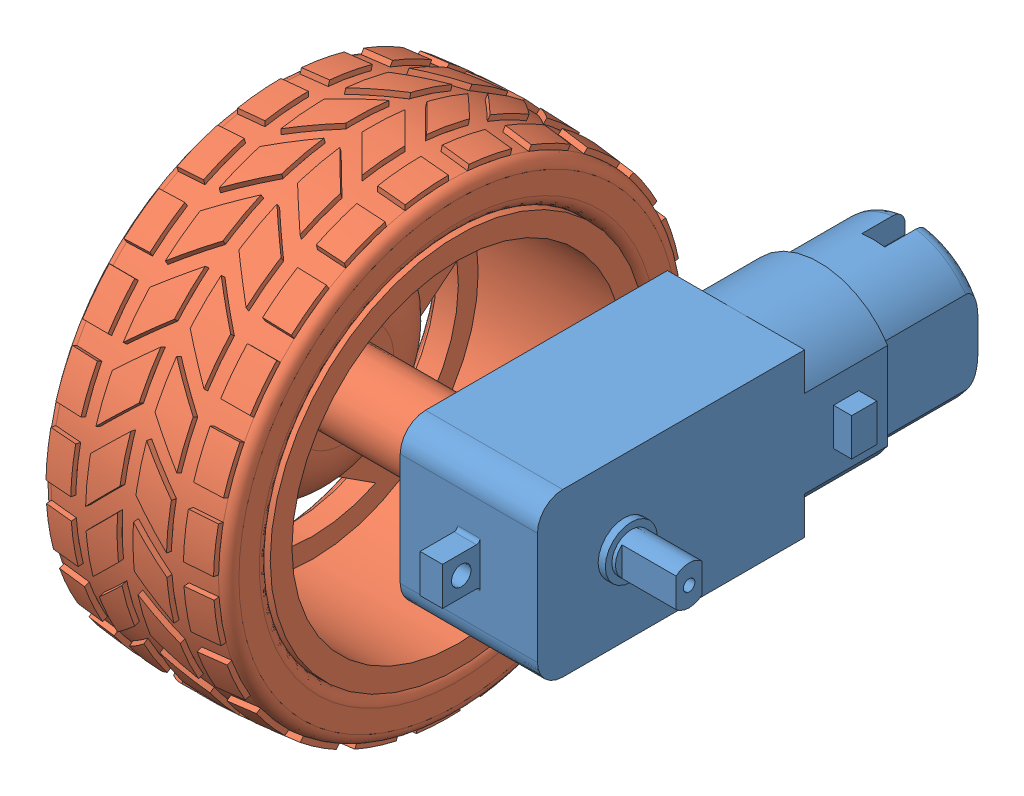
SolidWorks assembly yellow_motor_and_drive, configuration Default. Lengths in mm.
Overall size (58.5 67.18 87.05).
2 component instances, 2 part files, 3 mates.
Components (placement in the parent):
- yellow_drive-1: yellow_drive [Default] at origin size (37 22.5 70.7)
- yellow_wheel-1: yellow_wheel [Default] at (-1.5 0 25) x (0 0 -1) z (1 0 0) size (67.15 67.18 29)
Mates (geometry in assembly coordinates):
- Concentric1: concentric: cylinder of yellow_drive-1 through (-9 0 25) axis (1 0 0) radius 2.7; cylinder of yellow_wheel-1 through (-1.5 0 25) axis (1 0 0) radius 5
- Coincident1: coincident: plane of yellow_drive-1 through (-1.5 0 26.8) normal (0 0 1); plane of yellow_wheel-1 through (-32.49 0 26.8) normal (0 0 -1)
- Coincident2: coincident anti-aligned: plane of yellow_drive-1 through (-1.5 0 0) normal (-1 0 0); plane of yellow_wheel-1 through (-1.5 0 25) normal (1 0 0)
